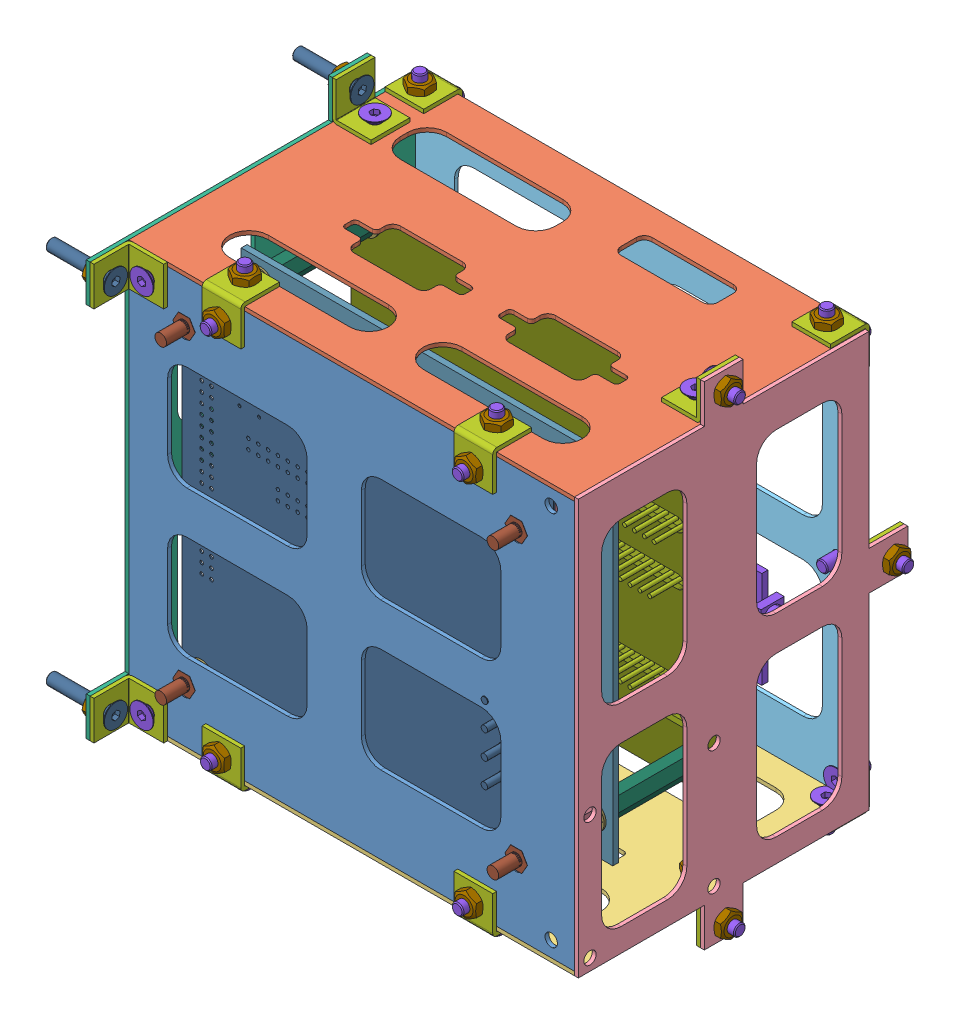
SolidWorks assembly avionics_reassemb, configuration Default. Lengths in mm.
Overall size (134.36 127 95).
180 component instances, 47 part files, 18 mates.
Components (placement in the parent):
- PCB_board_box_reassemb-1: PCB_board_box_reassemb [Default] at (0 -1.2351 -1.0546) size (121.33 127 95)
  - PCB_board_box_buttom-1: PCB_board_box_buttom [Default] at origin size (115 105 1)
  - PCB_board_box_front-1: PCB_board_box_front [Default] at (0 53.5 -36.5) x (0 0 -1) z (0 -1 0) size (75 115 1)
  - PCB_board_box_back-1: PCB_board_box_back [Default] at (0 -53.5 -36.5) x (0 0 1) z (0 1 0) size (75 115 1)
  - PCB_board_box_right-1: PCB_board_box_right [Default] at (58.5 0 -36.5) x (0 0 1) z (-1 0 0) size (85 127 1)
  - PCB_board_box_top-1: PCB_board_box_top [Default] at (0 0 -74) x (0 -1 0) z (0 0 1) size (105 115 1)
  - PCB_board_box_left-1: PCB_board_box_left [Default] at (-57.5 0 -36.5) x (0 0 1) z (-1 0 0) size (85 127 1)
  - connector_1-1: connector_1 [Default] at (-32.5 49.6 2.1) x (1 0 0) z (0 0 -1) size (10 10 10)
  - connector_1-2: connector_1 [Default] at (57.5 58.5 -36.5) x (0 0 1) z (-1 0 0) size (10 10 10)
  - connector_1-3: connector_1 [Default] at (57.5 -58.5 -36.5) x (0 0 -1) z (-1 0 0) size (10 10 10)
  - connector_1-4: connector_1 [Default] at (32.5 -49.6 2.1) x (-1 0 0) z (0 0 -1) size (10 10 10)
  - connector_1-5: connector_1 [Default] at (-32.5 -49.6 2.1) x (-1 0 0) z (0 0 -1) size (10 10 10)
  - connector_1-6: connector_1 [Default] at (-57.5 48.5 6) x (0 1 0) z (1 0 0) size (10 10 10)
  - connector_1-7: connector_1 [Default] at (-57.5 -48.5 6) x (0 1 0) z (1 0 0) size (10 10 10)
  - connector_1-8: connector_1 [Default] at (-57.5 58.5 -56.5) x (0 0 -1) z (1 0 0) size (10 10 10)
  - connector_1-9: connector_1 [Default] at (-57.5 -58.5 -56.5) x (0 0 1) z (1 0 0) size (10 10 10)
  - connector_1-10: connector_1 [Default] at (52.5 0 -74) x (0 -1 0) z (0 0 -1) size (10 10 10)
  - connector_1-11: connector_1 [Default] at (52.5 -49.6 -75.1) size (10 10 10)
  - connector_1-12: connector_1 [Default] at (-52.5 -54.6 -70.1) x (-1 0 0) z (0 1 0) size (10 10 10)
  - connector_1-13: connector_1 [Default] at (-52.5 49.6 -75.1) x (-1 0 0) z (0 0 1) size (10 10 10)
  - connector_1-14: connector_1 [Default] at (32.5 49.6 2.1) x (1 0 0) z (0 0 -1) size (10 10 10)
  - connector_1-15: connector_1 [Default] at (52.5 49.6 -75.1) x (-1 0 0) z (0 0 1) size (10 10 10)
  - ISO 10642 - M3 x  8-1: ISO 10642 - M3 x  8 [Default] at (-52.5 48.6 -71.3293) x (0 0 -1) z (-1 0 0) size (8 6 6)
  - ISO 10642 - M3 x  8-2: ISO 10642 - M3 x  8 [Default] at (-52.5 50.8293 -69.1) x (0 1 0) z (-1 0 0) size (8 6 6)
  - ISO 10642 - M3 x  8-3: ISO 10642 - M3 x  8 [Default] at (-52.5 -48.6 -71.3293) x (0 0 -1) z (-1 0 0) size (8 6 6)
  - ISO 10642 - M3 x  8-4: ISO 10642 - M3 x  8 [Default] at (-52.5 -50.8293 -69.1) x (0 -1 0) z (-1 0 0) size (8 6 6)
  - ISO 10642 - M3 x  8-5: ISO 10642 - M3 x  8 [Default] at (52.5 -50.7586 -69.1) x (0 -1 0) z (-1 0 0) size (8 6 6)
  - ISO 10642 - M3 x  8-6: ISO 10642 - M3 x  8 [Default] at (52.5 -48.6 -71.2586) x (0 0 -1) z (-1 0 0) size (8 6 6)
  - ISO 10642 - M3 x  8-7: ISO 10642 - M3 x  8 [Default] at (32.5 -48.6 -1.7414) x (0 0 1) z (-1 0 0) size (8 6 6)
  - ISO 10642 - M3 x  8-8: ISO 10642 - M3 x  8 [Default] at (32.5 -50.7586 -3.9) x (0 -1 0) z (-1 0 0) size (8 6 6)
  - ISO 10642 - M3 x  8-9: ISO 10642 - M3 x  8 [Default] at (-32.5 -48.6 -1.7414) x (0 0 1) z (-1 0 0) size (8 6 6)
  - ISO 10642 - M3 x  8-10: ISO 10642 - M3 x  8 [Default] at (-32.5 -50.7586 -3.9) x (0 -1 0) z (-1 0 0) size (8 6 6)
  - ISO 10642 - M3 x  8-11: ISO 10642 - M3 x  8 [Default] at (32.5 48.6 -1.7414) x (0 0 1) z (-1 0 0) size (8 6 6)
  - ISO 10642 - M3 x  8-12: ISO 10642 - M3 x  8 [Default] at (32.5 50.7586 -3.9) x (0 1 0) z (-1 0 0) size (8 6 6)
  - ISO 10642 - M3 x  8-13: ISO 10642 - M3 x  8 [Default] at (-32.5 48.6 -1.6707) x (0 0 1) z (-1 0 0) size (8 6 6)
  - ISO 10642 - M3 x  8-14: ISO 10642 - M3 x  8 [Default] at (-32.5 50.7586 -3.9) x (0 1 0) z (-1 0 0) size (8 6 6)
  - ISO 10642 - M3 x  8-15: ISO 10642 - M3 x  8 [Default] at (52.5 48.6 -71.2586) x (0 0 -1) z (-1 0 0) size (8 6 6)
  - ISO 10642 - M3 x  8-16: ISO 10642 - M3 x  8 [Default] at (52.5 50.7586 -69.1) x (0 1 0) z (-1 0 0) size (8 6 6)
  - ISO 10642 - M3 x  8-17: ISO 10642 - M3 x  8 [Default] at (51.5 0 -76.7414) x (0 0 1) z (-1 0 0) size (8 6 6)
  - ISO 10642 - M3 x  8-18: ISO 10642 - M3 x  8 [Default] at (54.7586 0 -80) x (1 0 0) z (0 0 -1) size (8 6 6)
  - ISO 10642 - M3 x  8-19: ISO 10642 - M3 x  8 [Default] at (54.7586 -59.5 -36.5) x (1 0 0) z (0 0 -1) size (8 6 6)
  - ISO 10642 - M3 x  8-20: ISO 10642 - M3 x  8 [Default] at (51.5 -56.2414 -36.5) x (0 1 0) z (-1 0 0) size (8 6 6)
  - ISO 10642 - M3 x  8-21: ISO 10642 - M3 x  8 [Default] at (51.5 56.2414 -36.5) x (0 -1 0) z (-1 0 0) size (8 6 6)
  - ISO 10642 - M3 x  8-22: ISO 10642 - M3 x  8 [Default] at (54.8293 59.5 -36.5) x (1 0 0) z (0 0 -1) size (8 6 6)
  - ISO 10642 - M3 x  8-23: ISO 10642 - M3 x  8 [Default] at (-51.5 56.1707 -56.5) x (0 -1 0) z (-1 0 0) size (8 6 6)
  - ISO 10642 - M3 x  8-25: ISO 10642 - M3 x  8 [Default] at (-51.5 48.5 3.7414) x (0 0 -1) z (-1 0 0) size (8 6 6)
  - ISO 10642 - M3 x  8-28: ISO 10642 - M3 x  8 [Default] at (-51.5 -48.5 3.7414) x (0 0 -1) z (-1 0 0) size (8 6 6)
  - ISO 10642 - M3 x  8-30: ISO 10642 - M3 x  8 [Default] at (-51.5 -56.1707 -56.5) x (0 1 0) z (-1 0 0) size (8 6 6)
  - ISO 4032 - M3-1: ISO 4032 - M3 [Default] at (-52.5 48.6 -77.5) x (0 0 1) z (-1 0 0) size (2.4 6.35 5.5)
  - ISO 4032 - M3-2: ISO 4032 - M3 [Default] at (-52.5 54.6 -69.1) x (0 1 0) z (-1 0 0) size (2.4 6.35 5.5)
  - ISO 4032 - M3-3: ISO 4032 - M3 [Default] at (-51.5 52.5 -56.5) x (0 -1 0) z (-1 0 0) size (2.4 6.35 5.5)
  - ISO 4032 - M3-4: ISO 4032 - M3 [Default] at (-52.5 -48.6 -75.1) x (0 0 -1) z (-1 0 0) size (2.4 6.35 5.5)
  - ISO 4032 - M3-5: ISO 4032 - M3 [Default] at (-52.5 -54.6 -69.1) x (0 -1 0) z (-1 0 0) size (2.4 6.35 5.5)
  - ISO 4032 - M3-6: ISO 4032 - M3 [Default] at (-51.5 -52.5 -56.5) x (0 1 0) z (-1 0 0) size (2.4 6.35 5.5)
  - ISO 4032 - M3-7: ISO 4032 - M3 [Default] at (-51.5 -48.5 0) x (0 0 -1) z (-1 0 0) size (2.4 6.35 5.5)
  - ISO 4032 - M3-8: ISO 4032 - M3 [Default] at (-51.5 48.5 0) x (0 0 -1) z (-1 0 0) size (2.4 6.35 5.5)
  - ISO 4032 - M3-9: ISO 4032 - M3 [Default] at (-32.5 57 -3.9) x (0 -1 0) z (-1 0 0) size (2.4 6.35 5.5)
  - ISO 4032 - M3-10: ISO 4032 - M3 [Default] at (-32.5 48.6 4.5) x (0 0 -1) z (-1 0 0) size (2.4 6.35 5.5)
  - ISO 4032 - M3-11: ISO 4032 - M3 [Default] at (-32.5 -48.6 2.1) x (0 0 1) z (-1 0 0) size (2.4 6.35 5.5)
  - ISO 4032 - M3-12: ISO 4032 - M3 [Default] at (-32.5 -57 -3.9) x (0 1 0) z (-1 0 0) size (2.4 6.35 5.5)
  - ISO 4032 - M3-13: ISO 4032 - M3 [Default] at (52.5 -48.6 -75.1) x (0 0 -1) z (-1 0 0) size (2.4 6.35 5.5)
  - ISO 4032 - M3-14: ISO 4032 - M3 [Default] at (52.5 -54.6 -69.1) x (0 -1 0) z (-1 0 0) size (2.4 6.35 5.5)
  - ISO 4032 - M3-15: ISO 4032 - M3 [Default] at (52.5 48.6 -75.1) x (0 0 -1) z (-1 0 0) size (2.4 6.35 5.5)
  - ISO 4032 - M3-16: ISO 4032 - M3 [Default] at (52.5 54.6 -69.1) x (0 1 0) z (-1 0 0) size (2.4 6.35 5.5)
  - ISO 4032 - M3-17: ISO 4032 - M3 [Default] at (32.5 57 -3.9) x (0 -1 0) z (-1 0 0) size (2.4 6.35 5.5)
  - ISO 4032 - M3-18: ISO 4032 - M3 [Default] at (32.5 48.6 4.5) x (0 0 -1) z (-1 0 0) size (2.4 6.35 5.5)
  - ISO 4032 - M3-19: ISO 4032 - M3 [Default] at (32.5 -48.6 4.5) x (0 0 -1) z (-1 0 0) size (2.4 6.35 5.5)
  - ISO 4032 - M3-20: ISO 4032 - M3 [Default] at (32.5 -57 -3.9) x (0 1 0) z (-1 0 0) size (2.4 6.35 5.5)
  - ISO 4032 - M3-21: ISO 4032 - M3 [Default] at (51.5 -52.5 -36.5) x (0 1 0) z (-1 0 0) size (2.4 6.35 5.5)
  - ISO 4032 - M3-22: ISO 4032 - M3 [Default] at (51.5 52.5 -36.5) x (0 -1 0) z (-1 0 0) size (2.4 6.35 5.5)
  - ISO 4032 - M3-23: ISO 4032 - M3 [Default] at (58.5 0 -80) size (2.4 6.35 5.5)
  - ISO 4032 - M3-24: ISO 4032 - M3 [Default] at (58.5 -59.5 -36.5) size (2.4 6.35 5.5)
  - ISO 4032 - M3-25: ISO 4032 - M3 [Default] at (58.5 59.5 -36.5) size (2.4 6.35 5.5)
- PCB-1: PCB [Default] at (47.6465 -44.1479 -4.8556) x (0 1 0) z (0 0 -1) size (96.55 95.89 17.8)
- copper_pillar_M3_L15-1: copper_pillar_M3_L15 [Default] at (42.5 -36.16 0) x (1 0 0) z (0 1 0) size (5.77 16 5)
- copper_pillar_M3_L15-2: copper_pillar_M3_L15 [Default] at (-43.225 40.04 0) x (1 0 0) z (0 1 0) size (5.77 16 5)
- copper_pillar_M3_L15-3: copper_pillar_M3_L15 [Default] at (42.5 37.5 0) x (1 0 0) z (0 1 0) size (5.77 16 5)
- copper_pillar_M3_L15-4: copper_pillar_M3_L15 [Default] at (-43.225 -39.97 0) x (1 0 0) z (0 1 0) size (5.77 16 5)
- washerM3x0.5h-1: washerM3x0.5h [Default] at (-43.225 -39.97 -4.5) size (6.7 6.7 0.5)
- washerM3x0.5h-2: washerM3x0.5h [Default] at (42.5 -36.16 -4.5) size (6.7 6.7 0.5)
- washerM3x0.5h-3: washerM3x0.5h [Default] at (-43.225 40.04 -4) x (1 0 0) z (0 0 -1) size (6.7 6.7 0.5)
- washerM3x0.5h-4: washerM3x0.5h [Default] at (42.5 37.5 -4) x (1 0 0) z (0 0 -1) size (6.7 6.7 0.5)
- copper_pillar_M3_L15_1-1: copper_pillar_M3_L15_1 [Default] at (42.5 -36.16 -5.3556) x (1 0 0) z (0 1 0) size (5.77 26 5)
- copper_pillar_M3_L15_1-2: copper_pillar_M3_L15_1 [Default] at (42.5 37.5 -5.3556) x (1 0 0) z (0 1 0) size (5.77 26 5)
- copper_pillar_M3_L15_1-3: copper_pillar_M3_L15_1 [Default] at (-43.225 40.04 -5.3556) x (1 0 0) z (0 1 0) size (5.77 26 5)
- copper_pillar_M3_L15_1-4: copper_pillar_M3_L15_1 [Default] at (-43.225 -39.97 -5.3556) x (1 0 0) z (0 1 0) size (5.77 26 5)
- washerM3x0.5h-5: washerM3x0.5h [Default] at (-43.225 40.04 -5.3556) size (6.7 6.7 0.5)
- washerM3x0.5h-6: washerM3x0.5h [Default] at (-43.225 -39.97 -4.8556) x (1 0 0) z (0 0 -1) size (6.7 6.7 0.5)
- washerM3x0.5h-7: washerM3x0.5h [Default] at (42.5 -36.16 -4.8556) x (1 0 0) z (0 0 -1) size (6.7 6.7 0.5)
- washerM3x0.5h-8: washerM3x0.5h [Default] at (42.5 37.5 -4.8556) x (1 0 0) z (0 0 -1) size (6.7 6.7 0.5)
- washerM3x0.5h-9: washerM3x0.5h [Default] at (-43.225 40.04 -19.3556) x (1 0 0) z (0 0 -1) size (6.7 6.7 0.5)
- washerM3x0.5h-10: washerM3x0.5h [Default] at (-43.225 -39.97 -19.3556) x (1 0 0) z (0 0 -1) size (6.7 6.7 0.5)
- washerM3x0.5h-11: washerM3x0.5h [Default] at (42.5 -36.16 -19.3556) x (1 0 0) z (0 0 -1) size (6.7 6.7 0.5)
- washerM3x0.5h-12: washerM3x0.5h [Default] at (42.5 37.5 -19.3556) x (1 0 0) z (0 0 -1) size (6.7 6.7 0.5)
- STM32 Communication Board ver1.0-1: STM32 Communication Board ver1.0 [Default] at (42.5 -36.16 -21.3601) x (0 1 0) z (0 0 -1) size (90.17 95.89 10)
- washerM3x0.5h-13: washerM3x0.5h [Default] at (42.5 -36.16 -21.3601) x (1 0 0) z (0 0 -1) size (6.7 6.7 0.5)
- washerM3x0.5h-14: washerM3x0.5h [Default] at (-43.225 -39.97 -21.3601) x (1 0 0) z (0 0 -1) size (6.7 6.7 0.5)
- washerM3x0.5h-15: washerM3x0.5h [Default] at (42.5 37.5 -21.3601) x (1 0 0) z (0 0 -1) size (6.7 6.7 0.5)
- washerM3x0.5h-16: washerM3x0.5h [Default] at (-43.225 40.04 -21.3601) x (1 0 0) z (0 0 -1) size (6.7 6.7 0.5)
- copper_pillar_M3_L25_1-1: copper_pillar_M3_L25_1 [Default] at (-43.225 -39.97 -21.8601) x (1 0 0) z (0 1 0) size (5.77 37 5)
- copper_pillar_M3_L25_1-2: copper_pillar_M3_L25_1 [Default] at (42.5 -36.16 -21.8601) x (1 0 0) z (0 1 0) size (5.77 37 5)
- copper_pillar_M3_L25_1-3: copper_pillar_M3_L25_1 [Default] at (42.5 37.5 -21.8601) x (1 0 0) z (0 1 0) size (5.77 37 5)
- copper_pillar_M3_L25_1-4: copper_pillar_M3_L25_1 [Default] at (-43.225 40.04 -21.8601) x (1 0 0) z (0 1 0) size (5.77 37 5)
- washerM3x0.5h-17: washerM3x0.5h [Default] at (42.5 37.5 -47.3601) size (6.7 6.7 0.5)
- washerM3x0.5h-18: washerM3x0.5h [Default] at (-43.225 40.04 -46.8601) x (1 0 0) z (0 0 -1) size (6.7 6.7 0.5)
- washerM3x0.5h-19: washerM3x0.5h [Default] at (42.5 -36.16 -47.3601) size (6.7 6.7 0.5)
- washerM3x0.5h-20: washerM3x0.5h [Default] at (-43.225 -39.97 -47.3601) size (6.7 6.7 0.5)
- empty_board-1: empty_board [Default] at (0.08 0.12 -47.3601) x (0 1 0) z (-1 0 0) size (90 1.45 95)
- MTi-1_v3-1: MTi-1_v3 [Default] at (-8.5645 -18.7527 -51.9664) x (0 1 0) z (0 0 -1) size (53.34 66.07 22.31)
  - Board_1v2(2)^MTi-1-SoB_v2-1: Board_1v2(2)^MTi-1-SoB_v2 [Default] at origin size (12.15 12.15 1.56)
    - Open CASCADE STEP translator 6.8 2.1.1^Board_1v2(2)_MTi-1-SoB_v2-1: Open CASCADE STEP translator 6.8 2.1.1^Board_1v2(2)_MTi-1-SoB_v2 [Default] at (0 0 -1.5563) size (12.15 12.15 1.56)
      - Open CASCADE STEP translator 6.8 2.1.1.1^Open CASCADE STEP translator_ 6.8 2.1.1_Board_1v2(2)_MTi-1-SoB_v2-1: Open CASCADE STEP translator 6.8 2.1.1.1^Open CASCADE STEP translator_ 6.8 2.1.1_Board_1v2(2)_MTi-1-SoB_v2 [Default] at origin size (12.15 12.15 1.56)
  - U200_1v2(2)^MTi-1-SoB_v2-1: U200_1v2(2)^MTi-1-SoB_v2 [Default] at origin size (3.1 3.3 0.6)
    - 7460079024(2)^U200_1v2(2)_MTi-1-SoB_v2-1: 7460079024(2)^U200_1v2(2)_MTi-1-SoB_v2 [Default] at (5.6 3.4 0) size (3.1 3.3 0.6)
      - Extruded(2)^7460079024(2)_U200_1v2(2)_MTi-1-SoB_v2-1: Extruded(2)^7460079024(2)_U200_1v2(2)_MTi-1-SoB_v2 [Default] at origin size (3.1 3.3 0.6)
  - C200_1v2(2)^MTi-1-SoB_v2-1: C200_1v2(2)^MTi-1-SoB_v2 [Default] at origin size (1.05 0.55 0.55)
    - Cap_0402(2)^C200_1v2(2)_MTi-1-SoB_v2-1: Cap_0402(2)^C200_1v2(2)_MTi-1-SoB_v2 [Default] at (5.3999 6.9749 0.26) x (-1 0 0) z (0 0 1) size (1.05 0.55 0.55)
  - C201_1v2(2)^MTi-1-SoB_v2-1: C201_1v2(2)^MTi-1-SoB_v2 [Default] at origin size (1.05 0.55 0.55)
    - Cap_0402(2)^C201_1v2(2)_MTi-1-SoB_v2-1: Cap_0402(2)^C201_1v2(2)_MTi-1-SoB_v2 [Default] at (6.7999 1.375 0.26) x (-1 0 0) z (0 0 1) size (1.05 0.55 0.55)
  - C204_1v2(2)^MTi-1-SoB_v2-1: C204_1v2(2)^MTi-1-SoB_v2 [Default] at origin size (1.05 0.55 0.55)
    - Cap_0402(2)^C204_1v2(2)_MTi-1-SoB_v2-1: Cap_0402(2)^C204_1v2(2)_MTi-1-SoB_v2 [Default] at (8.1999 3.0749 0.26) x (-1 0 0) z (0 0 1) size (1.05 0.55 0.55)
  - C205_1v2(2)^MTi-1-SoB_v2-1: C205_1v2(2)^MTi-1-SoB_v2 [Default] at origin size (1.05 0.55 0.55)
    - Cap_0402(2)^C205_1v2(2)_MTi-1-SoB_v2-1: Cap_0402(2)^C205_1v2(2)_MTi-1-SoB_v2 [Default] at (4.2001 0.8251 0.26) x (1 0 0) z (0 0 1) size (1.05 0.55 0.55)
  - C206_1v2(2)^MTi-1-SoB_v2-1: C206_1v2(2)^MTi-1-SoB_v2 [Default] at origin size (0.55 1.05 0.55)
    - Cap_0402(2)^C206_1v2(2)_MTi-1-SoB_v2-1: Cap_0402(2)^C206_1v2(2)_MTi-1-SoB_v2 [Default] at (3.1251 4.5999 0.26) x (0 -1 0) z (0 0 1) size (1.05 0.55 0.55)
  - C207_1v2(2)^MTi-1-SoB_v2-1: C207_1v2(2)^MTi-1-SoB_v2 [Default] at origin size (1.05 0.55 0.55)
    - Cap_0402(2)^C207_1v2(2)_MTi-1-SoB_v2-1: Cap_0402(2)^C207_1v2(2)_MTi-1-SoB_v2 [Default] at (7.3001 5.4251 0.26) x (1 0 0) z (0 0 1) size (1.05 0.55 0.55)
  - C208_1v2(2)^MTi-1-SoB_v2-1: C208_1v2(2)^MTi-1-SoB_v2 [Default] at origin size (0.55 1.05 0.55)
    - Cap_0402(2)^C208_1v2(2)_MTi-1-SoB_v2-1: Cap_0402(2)^C208_1v2(2)_MTi-1-SoB_v2 [Default] at (3.1251 2.5999 0.26) x (0 -1 0) z (0 0 1) size (1.05 0.55 0.55)
  - C209_1v2(2)^MTi-1-SoB_v2-1: C209_1v2(2)^MTi-1-SoB_v2 [Default] at origin size (1.05 0.55 0.55)
    - Cap_0402(2)^C209_1v2(2)_MTi-1-SoB_v2-1: Cap_0402(2)^C209_1v2(2)_MTi-1-SoB_v2 [Default] at (8.6001 1.4251 0.26) x (1 0 0) z (0 0 1) size (1.05 0.55 0.55)
  - C300_1v2(2)^MTi-1-SoB_v2-1: C300_1v2(2)^MTi-1-SoB_v2 [Default] at origin size (0.55 1.05 0.55)
    - Cap_0402(2)^C300_1v2(2)_MTi-1-SoB_v2-1: Cap_0402(2)^C300_1v2(2)_MTi-1-SoB_v2 [Default] at (10.425 8.2999 0.26) x (0 -1 0) z (0 0 1) size (1.05 0.55 0.55)
  - C301_1v2(2)^MTi-1-SoB_v2-1: C301_1v2(2)^MTi-1-SoB_v2 [Default] at origin size (1.05 0.55 0.55)
    - Cap_0402(2)^C301_1v2(2)_MTi-1-SoB_v2-1: Cap_0402(2)^C301_1v2(2)_MTi-1-SoB_v2 [Default] at (3.4001 10.375 0.26) x (1 0 0) z (0 0 1) size (1.05 0.55 0.55)
  - C302_1v2(2)^MTi-1-SoB_v2-1: C302_1v2(2)^MTi-1-SoB_v2 [Default] at origin size (1.05 0.55 0.55)
    - Cap_0402(2)^C302_1v2(2)_MTi-1-SoB_v2-1: Cap_0402(2)^C302_1v2(2)_MTi-1-SoB_v2 [Default] at (5.5999 8.0749 0.26) x (-1 0 0) z (0 0 1) size (1.05 0.55 0.55)
  - C303_1v2(2)^MTi-1-SoB_v2-1: C303_1v2(2)^MTi-1-SoB_v2 [Default] at origin size (1.05 0.55 0.55)
    - Cap_0402(2)^C303_1v2(2)_MTi-1-SoB_v2-1: Cap_0402(2)^C303_1v2(2)_MTi-1-SoB_v2 [Default] at (7.2999 6.9749 0.26) x (-1 0 0) z (0 0 1) size (1.05 0.55 0.55)
  - C305_1v2(2)^MTi-1-SoB_v2-1: C305_1v2(2)^MTi-1-SoB_v2 [Default] at origin size (0.55 1.05 0.55)
    - Cap_0402(2)^C305_1v2(2)_MTi-1-SoB_v2-1: Cap_0402(2)^C305_1v2(2)_MTi-1-SoB_v2 [Default] at (6.4749 9.3001 0.26) x (0 1 0) z (0 0 1) size (1.05 0.55 0.55)
  - C304_1v2(2)^MTi-1-SoB_v2-1: C304_1v2(2)^MTi-1-SoB_v2 [Default] at origin size (0.55 1.05 0.55)
    - Cap_0402(2)^C304_1v2(2)_MTi-1-SoB_v2-1: Cap_0402(2)^C304_1v2(2)_MTi-1-SoB_v2 [Default] at (5.4749 9.3001 0.26) x (0 1 0) z (0 0 1) size (1.05 0.55 0.55)
  - R200_1v2(2)^MTi-1-SoB_v2-1: R200_1v2(2)^MTi-1-SoB_v2 [Default] at origin size (1 0.5 0.35)
    - RES0402(2)^R200_1v2(2)_MTi-1-SoB_v2-1: RES0402(2)^R200_1v2(2)_MTi-1-SoB_v2 [Default] at (-16.787 18.2331 0) x (-1 0 0) z (0 1 0) size (1 0.35 0.5)
  - R300_1v2(2)^MTi-1-SoB_v2-1: R300_1v2(2)^MTi-1-SoB_v2 [Default] at origin size (0.5 1 0.35)
    - RES0402(2)^R300_1v2(2)_MTi-1-SoB_v2-1: RES0402(2)^R300_1v2(2)_MTi-1-SoB_v2 [Default] at (13.6331 30.587 0) x (0 1 0) z (1 0 0) size (1 0.35 0.5)
  - R301_1v2(2)^MTi-1-SoB_v2-1: R301_1v2(2)^MTi-1-SoB_v2 [Default] at origin size (0.5 1 0.35)
    - RES0402(2)^R301_1v2(2)_MTi-1-SoB_v2-1: RES0402(2)^R301_1v2(2)_MTi-1-SoB_v2 [Default] at (21.9331 28.487 0) x (0 1 0) z (1 0 0) size (1 0.35 0.5)
  - S300_1v2(2)^MTi-1-SoB_v2-1: S300_1v2(2)^MTi-1-SoB_v2 [Default] at origin size (3 3 1)
    - 6752205952(2)^S300_1v2(2)_MTi-1-SoB_v2-1: 6752205952(2)^S300_1v2(2)_MTi-1-SoB_v2 [Default] at (8.4999 8.8999 0) size (3 3 1)
      - Extruded-1(2)^6752205952(2)_S300_1v2(2)_MTi-1-SoB_v2-1: Extruded-1(2)^6752205952(2)_S300_1v2(2)_MTi-1-SoB_v2 [Default] at origin size (3 3 1)
  - S301_1v2(2)^MTi-1-SoB_v2-1: S301_1v2(2)^MTi-1-SoB_v2 [Default] at origin size (2.5 3 0.86)
    - User_Library-LGA-14_2_5x3(2)^S301_1v2(2)_MTi-1-SoB_v2-1: User_Library-LGA-14_2_5x3(2)^S301_1v2(2)_MTi-1-SoB_v2 [Default] at (3.1 8.3 0.85) x (0 -1 0) z (1 0 0) size (3 0.86 2.5)
  - R302_1v2(2)^MTi-1-SoB_v2-1: R302_1v2(2)^MTi-1-SoB_v2 [Default] at origin size (0.5 1 0.35)
    - RES0402(2)^R302_1v2(2)_MTi-1-SoB_v2-1: RES0402(2)^R302_1v2(2)_MTi-1-SoB_v2 [Default] at (22.9331 28.487 0) x (0 1 0) z (1 0 0) size (1 0.35 0.5)
  - C202_1v2(2)^MTi-1-SoB_v2-1: C202_1v2(2)^MTi-1-SoB_v2 [Default] at origin size (1.05 0.55 0.55)
    - Cap_0402(2)^C202_1v2(2)_MTi-1-SoB_v2-1: Cap_0402(2)^C202_1v2(2)_MTi-1-SoB_v2 [Default] at (8.2001 4.4251 0.26) x (1 0 0) z (0 0 1) size (1.05 0.55 0.55)
  - C203_1v2(2)^MTi-1-SoB_v2-1: C203_1v2(2)^MTi-1-SoB_v2 [Default] at origin size (1.05 0.55 0.55)
    - Cap_0402(2)^C203_1v2(2)_MTi-1-SoB_v2-1: Cap_0402(2)^C203_1v2(2)_MTi-1-SoB_v2 [Default] at (8.2001 3.4251 0.26) x (1 0 0) z (0 0 1) size (1.05 0.55 0.55)
  - Y200_1v2(2)^MTi-1-SoB_v2-1: Y200_1v2(2)^MTi-1-SoB_v2 [Default] at origin size (1.61 2.01 0.31)
    - User_Library-Crystal_(NDK)_2.0x1.6(2)^Y200_1v2(2)_MTi-1-SoB_v2-1: User_Library-Crystal_(NDK)_2.0x1.6(2)^Y200_1v2(2)_MTi-1-SoB_v2 [Default] at (10.2 4.0001 0) x (0 -1 0) z (-1 0 0) size (2.01 0.31 1.61)
  - R303_1v2(2)^MTi-1-SoB_v2-1: R303_1v2(2)^MTi-1-SoB_v2 [Default] at origin size (0.5 1 0.35)
    - RES0402(2)^R303_1v2(2)_MTi-1-SoB_v2-1: RES0402(2)^R303_1v2(2)_MTi-1-SoB_v2 [Default] at (-1.8331 -11.987 0) x (0 -1 0) z (-1 0 0) size (1 0.35 0.5)
  - Mti-7 development board-1: Mti-7 development board [Default] at (6.7227 17.82 -3.1563) x (1 0 0) z (0 -1 0) size (53.34 18.51 57.52)
  - GNSS_board-1: GNSS_board [Default] at (6.6927 40.5245 6.9537) size (25 47 6)
- ISO 4032 - M3-1: ISO 4032 - M3 [Default] at (-43.225 -39.97 -48.8101) x (0 0 -1) z (1 0 0) size (2.4 6.35 5.5)
- ISO 4032 - M3-2: ISO 4032 - M3 [Default] at (-43.225 40.04 -48.8101) x (0 0 -1) z (1 0 0) size (2.4 6.35 5.5)
- ISO 4032 - M3-3: ISO 4032 - M3 [Default] at (42.5 -36.16 -50.4101) x (0 0 -1) z (1 0 0) size (2.4 6.35 5.5)
- ISO 4032 - M3-4: ISO 4032 - M3 [Default] at (42.5 37.5 -48.8101) x (0 0 -1) z (1 0 0) size (2.4 6.35 5.5)
- CUI_DEVICES_CFM-4010V-070-273-1: CUI_DEVICES_CFM-4010V-070-273 [Default] at (58.5 -34.5 -18) x (0 -1 0) z (0 0 1) size (0.06 0.01 0.07)
- screw- M3 x  15-1: screw- M3 x  15 [預設] at (-54.7586 58.2649 -57.5546) x (-1 0 0) z (0 -0.924225 -0.381849) size (16.7 6 6)
- ISO 4032 - M3-5: ISO 4032 - M3 [Default] at (-60.9 58.2649 -57.5546) x (1 0 0) z (0 1 0) size (2.4 6.35 5.5)
- ISO 4032 - M3-6: ISO 4032 - M3 [Default] at (-60.9 47.2649 5.9454) x (1 0 0) z (0 1 0) size (2.4 6.35 5.5)
- screw- M3 x  15-2: screw- M3 x  15 [預設] at (-54.8293 47.2649 5.9454) x (-1 0 0) z (0 -0.924225 -0.381849) size (16.7 6 6)
- screw- M3 x  15-3: screw- M3 x  15 [預設] at (-54.8293 -49.7351 5.9454) x (-1 0 0) z (0 -0.924225 -0.381849) size (16.7 6 6)
- ISO 4032 - M3-10: ISO 4032 - M3 [Default] at (-60.9 -49.7351 5.9454) x (1 0 0) z (0 1 0) size (2.4 6.35 5.5)
- screw- M3 x  15-4: screw- M3 x  15 [預設] at (-54.7586 -60.7351 -57.5546) x (-1 0 0) z (0 -0.924225 -0.381849) size (16.7 6 6)
- ISO 4032 - M3-11: ISO 4032 - M3 [Default] at (-60.9 -60.7351 -57.5546) x (1 0 0) z (0 1 0) size (2.4 6.35 5.5)
- LoRa_board.stp-1: LoRa_board.stp [預設] at (-21.3335 -13.7559 -18.2407) x (-1 0 0) z (0 1 0) size (36 8.9 77)
Mates (geometry in assembly coordinates):
- 同軸心1: concentric anti-aligned: cylinder of PCB_board_box_reassemb-1/connector_1-8 through (-57.5 58.2649 -57.5546) axis (1 0 0) radius 1.6; cylinder of screw- M3 x  15-1 through (-54.7586 58.2649 -57.5546) axis (-1 0 0) radius 1.5
- 重合/共線/共點1: coincident anti-aligned: plane of PCB_board_box_reassemb-1/connector_1-8 through (-56.5 57.2649 -57.5546) normal (1 0 0); circle of screw- M3 x  15-1
- 同軸心2: concentric anti-aligned: cylinder of screw- M3 x  15-1 through (-54.7586 58.2649 -57.5546) axis (-1 0 0) radius 1.5; cylinder of ISO 4032 - M3-5 through (-67.2375 58.2649 -57.5546) axis (1 0 0) radius 1.2295
- 重合/共線/共點2: coincident anti-aligned: plane of PCB_board_box_reassemb-1/PCB_board_box_left-1 through (-58.5 -1.2351 -37.5546) normal (-1 0 0); plane of ISO 4032 - M3-5 through (-58.5 58.2649 -57.5546) normal (1 0 0)
- 同軸心3: concentric anti-aligned: cylinder of ISO 4032 - M3-6 through (-67.2375 47.2649 5.9454) axis (1 0 0) radius 1.2295; cylinder of screw- M3 x  15-2 through (-54.8293 47.2649 5.9454) axis (-1 0 0) radius 1.5
- 同軸心6: concentric anti-aligned: cylinder of PCB_board_box_reassemb-1/connector_1-6 through (-57.5 47.2649 5.9454) axis (1 0 0) radius 1.6; cylinder of screw- M3 x  15-2 through (-54.8293 47.2649 5.9454) axis (-1 0 0) radius 1.5
- 重合/共線/共點5: coincident aligned: plane of PCB_board_box_reassemb-1/connector_1-6 through (-56.5 47.2649 4.9454) normal (1 0 0); circle of screw- M3 x  15-2
- 重合/共線/共點6: coincident anti-aligned: plane of PCB_board_box_reassemb-1/PCB_board_box_left-1 through (-58.5 -1.2351 -37.5546) normal (-1 0 0); plane of ISO 4032 - M3-6 through (-58.5 47.2649 5.9454) normal (1 0 0)
- 同軸心7: concentric anti-aligned: cylinder of screw- M3 x  15-3 through (-54.8293 -49.7351 5.9454) axis (-1 0 0) radius 1.5; cylinder of ISO 4032 - M3-10 through (-67.2375 -49.7351 5.9454) axis (1 0 0) radius 1.2295
- 同軸心8: concentric anti-aligned: cylinder of PCB_board_box_reassemb-1/connector_1-7 through (-57.5 -49.7351 5.9454) axis (1 0 0) radius 1.6; cylinder of screw- M3 x  15-3 through (-54.8293 -49.7351 5.9454) axis (-1 0 0) radius 1.5
- 重合/共線/共點8: coincident anti-aligned: plane of PCB_board_box_reassemb-1/PCB_board_box_left-1 through (-58.5 -1.2351 -37.5546) normal (-1 0 0); plane of ISO 4032 - M3-10 through (-58.5 -49.7351 5.9454) normal (1 0 0)
- 重合/共線/共點9: coincident aligned: plane of PCB_board_box_reassemb-1/connector_1-7 through (-56.5 -49.7351 4.9454) normal (1 0 0); circle of screw- M3 x  15-3
- 同軸心9: concentric anti-aligned: cylinder of screw- M3 x  15-4 through (-54.7586 -60.7351 -57.5546) axis (-1 0 0) radius 1.5; cylinder of ISO 4032 - M3-11 through (-67.2375 -60.7351 -57.5546) axis (1 0 0) radius 1.2295
- 同軸心10: concentric anti-aligned: cylinder of PCB_board_box_reassemb-1/connector_1-9 through (-57.5 -60.7351 -57.5546) axis (1 0 0) radius 1.6; cylinder of screw- M3 x  15-4 through (-54.7586 -60.7351 -57.5546) axis (-1 0 0) radius 1.5
- 重合/共線/共點10: coincident anti-aligned: plane of PCB_board_box_reassemb-1/PCB_board_box_left-1 through (-58.5 -1.2351 -37.5546) normal (-1 0 0); plane of ISO 4032 - M3-11 through (-58.5 -60.7351 -57.5546) normal (1 0 0)
- 重合/共線/共點11: coincident anti-aligned: plane of PCB_board_box_reassemb-1/connector_1-9 through (-56.5 -59.7351 -57.5546) normal (1 0 0); circle of screw- M3 x  15-4
- 同軸心11: concentric anti-aligned: circle of PCB-1; cylinder of LoRa_board.stp-1 through (-8.2335 18.8441 -16.5407) axis (0 0 1) radius 0.5
- 同軸心14: concentric anti-aligned: circle of PCB-1; cylinder of LoRa_board.stp-1 through (-31.0935 18.8441 -16.5407) axis (0 0 1) radius 0.5
